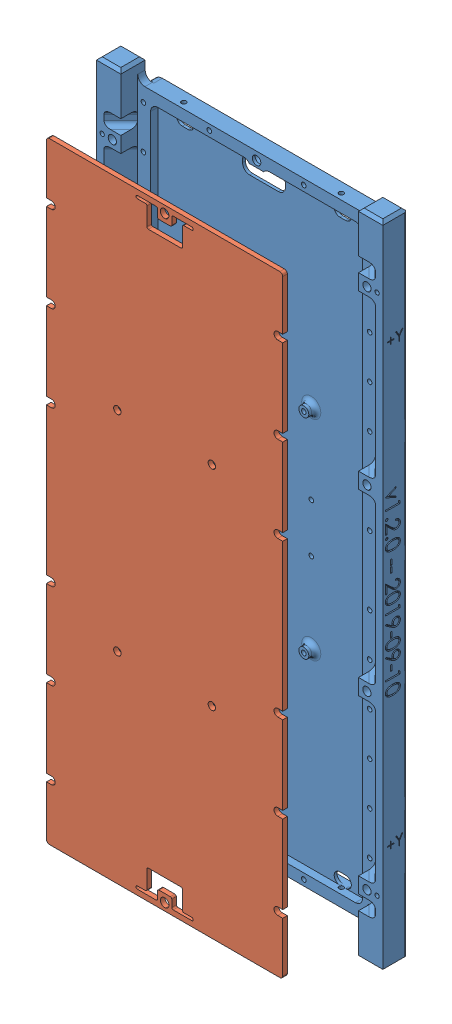
SolidWorks assembly backplanedefinition, configuration Default. Lengths in mm.
Overall size (278.46 278.2 145.75).
2 component instances, 2 part files, 2 mates.
Components (placement in the parent):
- Frame-1: Frame [-X] at (94.5315 120.7577 164.761) size (278.46 278.2 145.75)
- BackplaneBoardPCB-1: BackplaneBoardPCB [Default] at (94.5315 120.7577 197.8645) size (82.5 213.5 1.6)
Mates (geometry in assembly coordinates):
- Coincident1: coincident aligned: plane of Frame-1 through (94.5315 120.7577 164.761) normal (0 1 0); plane of BackplaneBoardPCBv3-1 through (94.5315 120.7577 197.8645) normal (0 1 0)
- Coincident2: coincident aligned: plane of Frame-1 through (94.5315 120.7577 164.761) normal (1 0 0); plane of BackplaneBoardPCBv3-1 through (94.5315 120.7577 197.8645) normal (1 0 0)
